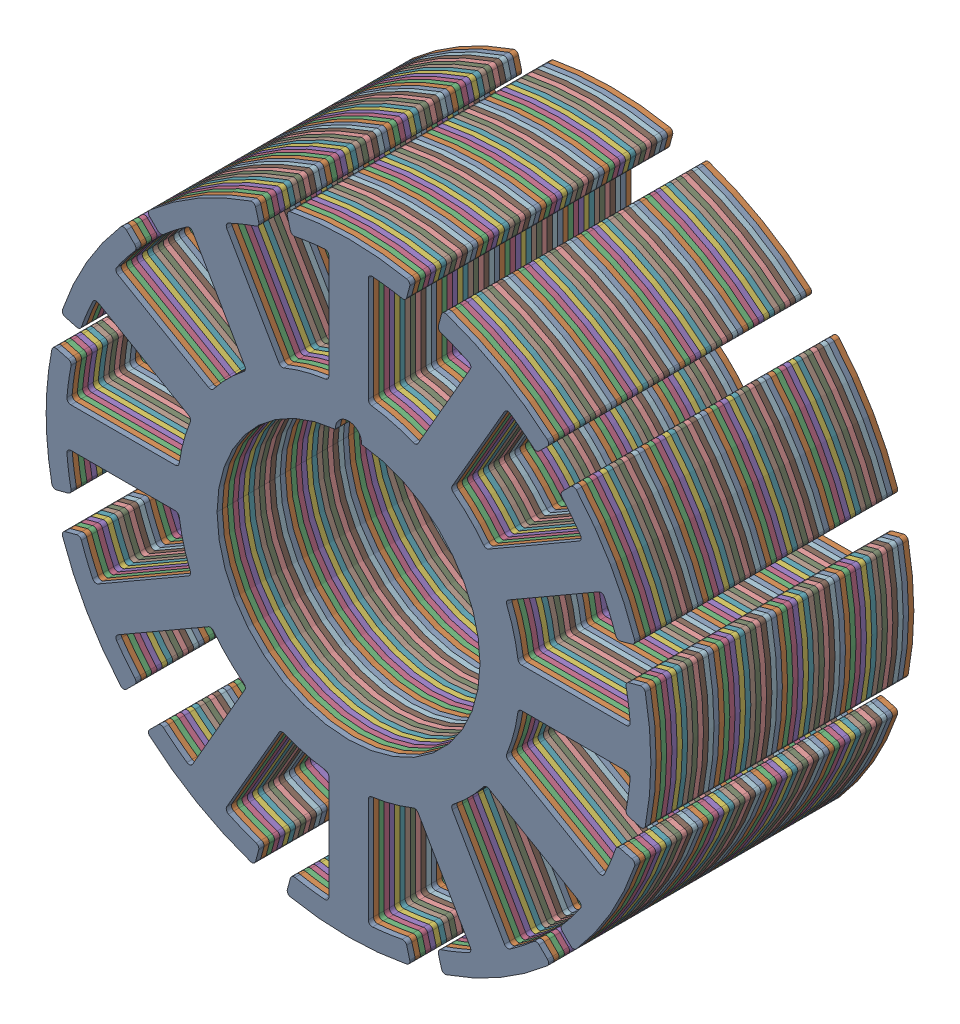
SolidWorks assembly 23x10x10mm-Stator.STEP, configuration Default. Lengths in mm.
Overall size (23 23 10).
62 component instances, 1 part files, 0 mates.
Components (placement in the parent):
- 23x10x5mm-Stator.STEP-1: 23x10x5mm-Stator.STEP [Default] at (-16.2466 9.1923 4.328) size (23 23 5)
  - 23x10x1mm-Stator.STEP-1: 23x10x1mm-Stator.STEP [Default] at (-15.1244 2.7036 6.5442) size (23 23 1)
    - 23x10-Stator-Plate.STEP-1: 23x10-Stator-Plate.STEP [Default] at (-25.8459 0.0676 13.4926) size (23 23 0.2)
    - 23x10-Stator-Plate.STEP-2: 23x10-Stator-Plate.STEP [Default] at (-25.8459 0.0676 13.2926) size (23 23 0.2)
    - 23x10-Stator-Plate.STEP-3: 23x10-Stator-Plate.STEP [Default] at (-25.8459 0.0676 13.0926) size (23 23 0.2)
    - 23x10-Stator-Plate.STEP-4: 23x10-Stator-Plate.STEP [Default] at (-25.8459 0.0676 12.8926) size (23 23 0.2)
    - 23x10-Stator-Plate.STEP-5: 23x10-Stator-Plate.STEP [Default] at (-25.8459 0.0676 12.6926) size (23 23 0.2)
  - 23x10x1mm-Stator.STEP-2: 23x10x1mm-Stator.STEP [Default] at (-15.1244 2.7036 5.5442) size (23 23 1)
    - 23x10-Stator-Plate.STEP-1: 23x10-Stator-Plate.STEP [Default] at (-25.8459 0.0676 13.4926) size (23 23 0.2)
    - 23x10-Stator-Plate.STEP-2: 23x10-Stator-Plate.STEP [Default] at (-25.8459 0.0676 13.2926) size (23 23 0.2)
    - 23x10-Stator-Plate.STEP-3: 23x10-Stator-Plate.STEP [Default] at (-25.8459 0.0676 13.0926) size (23 23 0.2)
    - 23x10-Stator-Plate.STEP-4: 23x10-Stator-Plate.STEP [Default] at (-25.8459 0.0676 12.8926) size (23 23 0.2)
    - 23x10-Stator-Plate.STEP-5: 23x10-Stator-Plate.STEP [Default] at (-25.8459 0.0676 12.6926) size (23 23 0.2)
  - 23x10x1mm-Stator.STEP-3: 23x10x1mm-Stator.STEP [Default] at (-15.1244 2.7036 4.5442) size (23 23 1)
    - 23x10-Stator-Plate.STEP-1: 23x10-Stator-Plate.STEP [Default] at (-25.8459 0.0676 13.4926) size (23 23 0.2)
    - 23x10-Stator-Plate.STEP-2: 23x10-Stator-Plate.STEP [Default] at (-25.8459 0.0676 13.2926) size (23 23 0.2)
    - 23x10-Stator-Plate.STEP-3: 23x10-Stator-Plate.STEP [Default] at (-25.8459 0.0676 13.0926) size (23 23 0.2)
    - 23x10-Stator-Plate.STEP-4: 23x10-Stator-Plate.STEP [Default] at (-25.8459 0.0676 12.8926) size (23 23 0.2)
    - 23x10-Stator-Plate.STEP-5: 23x10-Stator-Plate.STEP [Default] at (-25.8459 0.0676 12.6926) size (23 23 0.2)
  - 23x10x1mm-Stator.STEP-4: 23x10x1mm-Stator.STEP [Default] at (-15.1244 2.7036 3.5442) size (23 23 1)
    - 23x10-Stator-Plate.STEP-1: 23x10-Stator-Plate.STEP [Default] at (-25.8459 0.0676 13.4926) size (23 23 0.2)
    - 23x10-Stator-Plate.STEP-2: 23x10-Stator-Plate.STEP [Default] at (-25.8459 0.0676 13.2926) size (23 23 0.2)
    - 23x10-Stator-Plate.STEP-3: 23x10-Stator-Plate.STEP [Default] at (-25.8459 0.0676 13.0926) size (23 23 0.2)
    - 23x10-Stator-Plate.STEP-4: 23x10-Stator-Plate.STEP [Default] at (-25.8459 0.0676 12.8926) size (23 23 0.2)
    - 23x10-Stator-Plate.STEP-5: 23x10-Stator-Plate.STEP [Default] at (-25.8459 0.0676 12.6926) size (23 23 0.2)
  - 23x10x1mm-Stator.STEP-5: 23x10x1mm-Stator.STEP [Default] at (-15.1244 2.7036 2.5442) size (23 23 1)
    - 23x10-Stator-Plate.STEP-1: 23x10-Stator-Plate.STEP [Default] at (-25.8459 0.0676 13.4926) size (23 23 0.2)
    - 23x10-Stator-Plate.STEP-2: 23x10-Stator-Plate.STEP [Default] at (-25.8459 0.0676 13.2926) size (23 23 0.2)
    - 23x10-Stator-Plate.STEP-3: 23x10-Stator-Plate.STEP [Default] at (-25.8459 0.0676 13.0926) size (23 23 0.2)
    - 23x10-Stator-Plate.STEP-4: 23x10-Stator-Plate.STEP [Default] at (-25.8459 0.0676 12.8926) size (23 23 0.2)
    - 23x10-Stator-Plate.STEP-5: 23x10-Stator-Plate.STEP [Default] at (-25.8459 0.0676 12.6926) size (23 23 0.2)
- 23x10x5mm-Stator.STEP-2: 23x10x5mm-Stator.STEP [Default] at (-16.2466 9.1923 -0.672) size (23 23 5)
  - 23x10x1mm-Stator.STEP-1: 23x10x1mm-Stator.STEP [Default] at (-15.1244 2.7036 6.5442) size (23 23 1)
    - 23x10-Stator-Plate.STEP-1: 23x10-Stator-Plate.STEP [Default] at (-25.8459 0.0676 13.4926) size (23 23 0.2)
    - 23x10-Stator-Plate.STEP-2: 23x10-Stator-Plate.STEP [Default] at (-25.8459 0.0676 13.2926) size (23 23 0.2)
    - 23x10-Stator-Plate.STEP-3: 23x10-Stator-Plate.STEP [Default] at (-25.8459 0.0676 13.0926) size (23 23 0.2)
    - 23x10-Stator-Plate.STEP-4: 23x10-Stator-Plate.STEP [Default] at (-25.8459 0.0676 12.8926) size (23 23 0.2)
    - 23x10-Stator-Plate.STEP-5: 23x10-Stator-Plate.STEP [Default] at (-25.8459 0.0676 12.6926) size (23 23 0.2)
  - 23x10x1mm-Stator.STEP-2: 23x10x1mm-Stator.STEP [Default] at (-15.1244 2.7036 5.5442) size (23 23 1)
    - 23x10-Stator-Plate.STEP-1: 23x10-Stator-Plate.STEP [Default] at (-25.8459 0.0676 13.4926) size (23 23 0.2)
    - 23x10-Stator-Plate.STEP-2: 23x10-Stator-Plate.STEP [Default] at (-25.8459 0.0676 13.2926) size (23 23 0.2)
    - 23x10-Stator-Plate.STEP-3: 23x10-Stator-Plate.STEP [Default] at (-25.8459 0.0676 13.0926) size (23 23 0.2)
    - 23x10-Stator-Plate.STEP-4: 23x10-Stator-Plate.STEP [Default] at (-25.8459 0.0676 12.8926) size (23 23 0.2)
    - 23x10-Stator-Plate.STEP-5: 23x10-Stator-Plate.STEP [Default] at (-25.8459 0.0676 12.6926) size (23 23 0.2)
  - 23x10x1mm-Stator.STEP-3: 23x10x1mm-Stator.STEP [Default] at (-15.1244 2.7036 4.5442) size (23 23 1)
    - 23x10-Stator-Plate.STEP-1: 23x10-Stator-Plate.STEP [Default] at (-25.8459 0.0676 13.4926) size (23 23 0.2)
    - 23x10-Stator-Plate.STEP-2: 23x10-Stator-Plate.STEP [Default] at (-25.8459 0.0676 13.2926) size (23 23 0.2)
    - 23x10-Stator-Plate.STEP-3: 23x10-Stator-Plate.STEP [Default] at (-25.8459 0.0676 13.0926) size (23 23 0.2)
    - 23x10-Stator-Plate.STEP-4: 23x10-Stator-Plate.STEP [Default] at (-25.8459 0.0676 12.8926) size (23 23 0.2)
    - 23x10-Stator-Plate.STEP-5: 23x10-Stator-Plate.STEP [Default] at (-25.8459 0.0676 12.6926) size (23 23 0.2)
  - 23x10x1mm-Stator.STEP-4: 23x10x1mm-Stator.STEP [Default] at (-15.1244 2.7036 3.5442) size (23 23 1)
    - 23x10-Stator-Plate.STEP-1: 23x10-Stator-Plate.STEP [Default] at (-25.8459 0.0676 13.4926) size (23 23 0.2)
    - 23x10-Stator-Plate.STEP-2: 23x10-Stator-Plate.STEP [Default] at (-25.8459 0.0676 13.2926) size (23 23 0.2)
    - 23x10-Stator-Plate.STEP-3: 23x10-Stator-Plate.STEP [Default] at (-25.8459 0.0676 13.0926) size (23 23 0.2)
    - 23x10-Stator-Plate.STEP-4: 23x10-Stator-Plate.STEP [Default] at (-25.8459 0.0676 12.8926) size (23 23 0.2)
    - 23x10-Stator-Plate.STEP-5: 23x10-Stator-Plate.STEP [Default] at (-25.8459 0.0676 12.6926) size (23 23 0.2)
  - 23x10x1mm-Stator.STEP-5: 23x10x1mm-Stator.STEP [Default] at (-15.1244 2.7036 2.5442) size (23 23 1)
    - 23x10-Stator-Plate.STEP-1: 23x10-Stator-Plate.STEP [Default] at (-25.8459 0.0676 13.4926) size (23 23 0.2)
    - 23x10-Stator-Plate.STEP-2: 23x10-Stator-Plate.STEP [Default] at (-25.8459 0.0676 13.2926) size (23 23 0.2)
    - 23x10-Stator-Plate.STEP-3: 23x10-Stator-Plate.STEP [Default] at (-25.8459 0.0676 13.0926) size (23 23 0.2)
    - 23x10-Stator-Plate.STEP-4: 23x10-Stator-Plate.STEP [Default] at (-25.8459 0.0676 12.8926) size (23 23 0.2)
    - 23x10-Stator-Plate.STEP-5: 23x10-Stator-Plate.STEP [Default] at (-25.8459 0.0676 12.6926) size (23 23 0.2)
